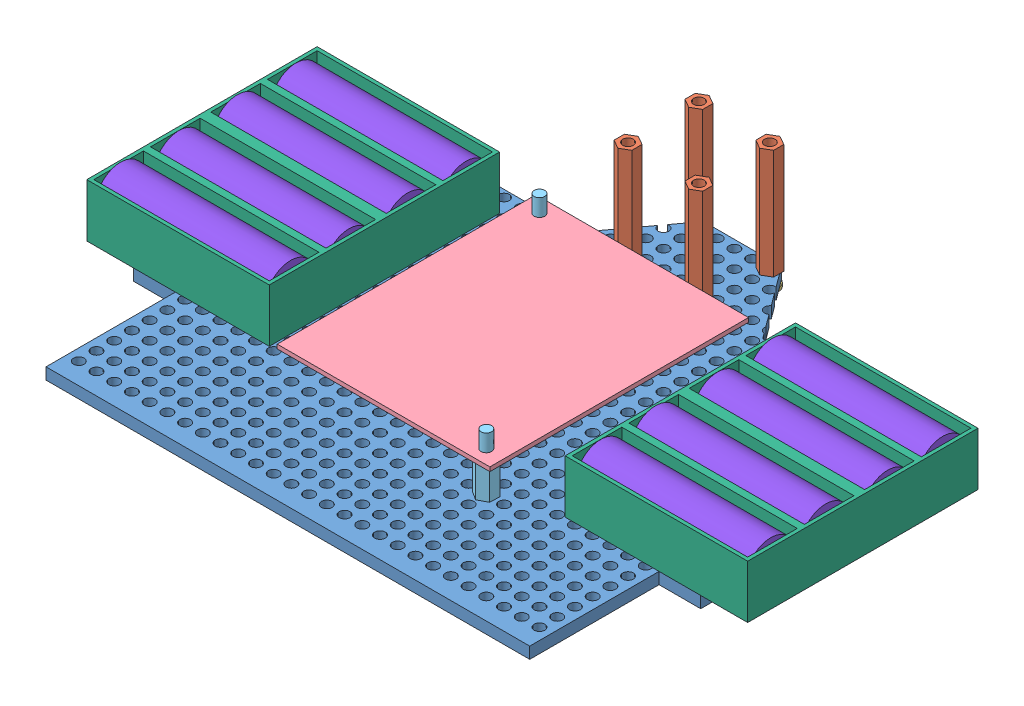
SolidWorks assembly 5-6-7, configuration Default. Lengths in mm.
Overall size (186.5 35.73 128.89).
32 component instances, 8 part files, 132 mates.
Components (placement in the parent):
- 6-0-1-1: 6-0-1 [Default] at origin size (160 3.25 128.29)
- 5-0-1-1: 5-0-1 [Default] at (10 3.25 -33.75) size (5 31 5.77)
- 5-0-1-2: 5-0-1 [Default] at (-10 3.25 -53.75) size (5 31 5.77)
- 5-0-1-3: 5-0-1 [Default] at (10 3.25 -53.75) size (5 31 5.77)
- 5-0-1-4: 5-0-1 [Default] at (-10 3.25 -33.75) size (5 31 5.77)
- 9-3-1-1: 9-3-1 [Default] at (10 9 -53.75) x (-1 0 0) z (0 0 1) size (5 10.48 5)
- 9-3-1-2: 9-3-1 [Default] at (-10 9 -33.75) x (1 0 0) z (0 0 -1) size (5 10.48 5)
- 9-3-1-3: 9-3-1 [Default] at (-10 9 -53.75) x (-1 0 0) z (0 0 1) size (5 10.48 5)
- 9-3-1-4: 9-3-1 [Default] at (10 9 -33.75) x (1 0 0) z (0 0 -1) size (5 10.48 5)
- 7-0-1-1: 7-0-1 [Default] at (0 13.25 8.75) size (60 1.17 73)
- 5-1-1-1: 5-1-1 [Default] at (-25 3.25 -23.75) size (5 16 5.77)
- 5-1-1-2: 5-1-1 [Default] at (25 3.25 41.25) x (0.999069 0 0.043139) z (-0.043139 0 0.999069) size (5 16 5.77)
- 9-3-1-5: 9-3-1 [Default] at (25 9 41.25) x (1 0 0) z (0 0 -1) size (5 10.48 5)
- 9-3-1-6: 9-3-1 [Default] at (-25 9 -23.75) x (1 0 0) z (0 0 -1) size (5 10.48 5)
- 6-1-1-5: 6-1-1 [Default] at (-67.5 3.25 3.25) size (51.5 15 65)
- 6-1-1-7: 6-1-1 [Default] at (67.5 3.25 3.25) size (51.5 15 65)
- 9-1-1-1: 9-1-1 [Default] at (-60 5 -18.75) x (-1 0 0) z (0 0 1) size (5 6.48 5)
- 9-1-1-2: 9-1-1 [Default] at (-60 5 16.25) x (-1 0 0) z (0 0 1) size (5 6.48 5)
- 9-1-1-3: 9-1-1 [Default] at (-75 5 -18.75) x (-1 0 0) z (0 0 1) size (5 6.48 5)
- 9-1-1-4: 9-1-1 [Default] at (-75 5 16.25) x (-1 0 0) z (0 0 1) size (5 6.48 5)
- 9-1-1-5: 9-1-1 [Default] at (60 5 -18.75) x (1 0 0) z (0 0 -1) size (5 6.48 5)
- 9-1-1-6: 9-1-1 [Default] at (60 5 16.25) x (-1 0 0) z (0 0 1) size (5 6.48 5)
- 9-1-1-7: 9-1-1 [Default] at (75 5 16.25) x (-1 0 0) z (0 0 1) size (5 6.48 5)
- 9-1-1-8: 9-1-1 [Default] at (75 5 -18.75) x (1 0 0) z (0 0 -1) size (5 6.48 5)
- 6-3-1-1: 6-3-1 [Default] at (-91.75 12.25 27.75) x (0 -1 0) z (0 0 1) size (14 49.5 14)
- 6-3-1-2: 6-3-1 [Default] at (-43.25 12.25 11.75) x (0 -1 0) z (0 0 -1) size (14 49.5 14)
- 6-3-1-3: 6-3-1 [Default] at (-91.75 12.25 -5.25) x (0 1 0) z (0 0 -1) size (14 49.5 14)
- 6-3-1-4: 6-3-1 [Default] at (-43.25 12.25 -21.25) x (0 -1 0) z (0 0 -1) size (14 49.5 14)
- 6-3-1-5: 6-3-1 [Default] at (91.75 12.25 27.75) x (0 1 0) z (0 0 1) size (14 49.5 14)
- 6-3-1-6: 6-3-1 [Default] at (43.25 12.25 11.75) x (0 -1 0) z (0 0 1) size (14 49.5 14)
- 6-3-1-7: 6-3-1 [Default] at (91.75 12.25 -5.25) x (0 1 0) z (0 0 1) size (14 49.5 14)
- 6-3-1-8: 6-3-1 [Default] at (43.25 12.25 -21.25) x (0 -1 0) z (0 0 1) size (14 49.5 14)
Mates (geometry in assembly coordinates):
- Coincident1: coincident anti-aligned: plane of 6-0-1-1 through (0 3.25 0) normal (0 1 0); plane of 5-0-1-3 through (10 3.25 -53.75) normal (0 -1 0)
- Parallel1: parallel aligned: plane of 6-0-1-1 through (0 0 0) normal (1 0 0); plane of 5-0-1-3 through (10 3.25 -53.75) normal (1 0 0)
- Concentric2: concentric aligned: cylinder of 6-0-1-1 through (10 3.25 -53.75) axis (0 -1 0) radius 1.5025; cylinder of 5-0-1-3 through (10 9.255 -53.75) axis (0 -1 0) radius 1.5025
- Coincident3: coincident anti-aligned: plane of 6-0-1-1 through (0 3.25 0) normal (0 1 0); plane of 5-0-1-2 through (-10 3.25 -53.75) normal (0 -1 0)
- Concentric3: concentric aligned: cylinder of 6-0-1-1 through (-10 3.25 -53.75) axis (0 -1 0) radius 1.5025; cylinder of 5-0-1-2 through (-10 9.255 -53.75) axis (0 -1 0) radius 1.5025
- Parallel2: parallel aligned: plane of 6-0-1-1 through (0 0 0) normal (1 0 0); plane of 5-0-1-2 through (-10 3.25 -53.75) normal (1 0 0)
- Coincident5: coincident anti-aligned: plane of 6-0-1-1 through (0 3.25 0) normal (0 1 0); plane of 5-0-1-4 through (-10 3.25 -33.75) normal (0 -1 0)
- Concentric4: concentric aligned: cylinder of 6-0-1-1 through (-10 3.25 -33.75) axis (0 -1 0) radius 1.5025; cylinder of 5-0-1-4 through (-10 9.255 -33.75) axis (0 -1 0) radius 1.5025
- Parallel3: parallel aligned: plane of 6-0-1-1 through (0 0 0) normal (1 0 0); plane of 5-0-1-4 through (-10 3.25 -33.75) normal (1 0 0)
- Coincident7: coincident anti-aligned: plane of 6-0-1-1 through (0 3.25 0) normal (0 1 0); plane of 5-0-1-1 through (10 3.25 -33.75) normal (0 -1 0)
- Concentric5: concentric aligned: cylinder of 6-0-1-1 through (10 3.25 -33.75) axis (0 -1 0) radius 1.5025; cylinder of 5-0-1-1 through (10 9.255 -33.75) axis (0 -1 0) radius 1.5025
- Parallel4: parallel aligned: plane of 6-0-1-1 through (0 0 0) normal (1 0 0); plane of 5-0-1-1 through (10 3.25 -33.75) normal (1 0 0)
- Concentric6: concentric anti-aligned: cylinder of 5-0-1-2 through (-10 9.255 -53.75) axis (0 -1 0) radius 1.5025; cylinder of 9-3-1-3 through (-10 0 -53.75) axis (0 1 0) radius 1.5
- Coincident9: coincident anti-aligned: plane of 6-0-1-1 through (0 0 0) normal (0 -1 0); plane of 9-3-1-3 through (-10 0 -53.75) normal (0 1 0)
- Parallel5: parallel anti-aligned: plane of 6-0-1-1 through (0 0 0) normal (1 0 0); plane of 9-3-1-3
- Concentric7: concentric anti-aligned: cylinder of 5-0-1-3 through (10 9.255 -53.75) axis (0 -1 0) radius 1.5025; cylinder of 9-3-1-1 through (10 0 -53.75) axis (0 1 0) radius 1.5
- Coincident11: coincident anti-aligned: plane of 6-0-1-1 through (0 0 0) normal (0 -1 0); plane of 9-3-1-1 through (10 0 -53.75) normal (0 1 0)
- Parallel6: parallel anti-aligned: plane of 6-0-1-1 through (0 0 0) normal (1 0 0); plane of 9-3-1-1
- Concentric8: concentric anti-aligned: cylinder of 5-0-1-4 through (-10 9.255 -33.75) axis (0 -1 0) radius 1.5025; cylinder of 9-3-1-2 through (-10 0 -33.75) axis (0 1 0) radius 1.5
- Coincident13: coincident anti-aligned: plane of 6-0-1-1 through (0 0 0) normal (0 -1 0); plane of 9-3-1-2 through (-10 0 -33.75) normal (0 1 0)
- Parallel7: parallel aligned: plane of 6-0-1-1 through (0 0 0) normal (1 0 0); plane of 9-3-1-2
- Concentric9: concentric anti-aligned: cylinder of 5-0-1-1 through (10 9.255 -33.75) axis (0 -1 0) radius 1.5025; cylinder of 9-3-1-4 through (10 0 -33.75) axis (0 1 0) radius 1.5
- Coincident15: coincident anti-aligned: plane of 6-0-1-1 through (0 0 0) normal (0 -1 0); plane of 9-3-1-4 through (10 0 -33.75) normal (0 1 0)
- Parallel8: parallel aligned: plane of 6-0-1-1 through (0 0 0) normal (1 0 0); plane of 9-3-1-4
- Coincident23: coincident anti-aligned: plane of 6-0-1-1 through (0 3.25 0) normal (0 1 0); plane of 5-1-1-1 through (-25 3.25 -23.75) normal (0 -1 0)
- Coincident24: coincident anti-aligned: plane of 6-0-1-1 through (0 3.25 0) normal (0 1 0); plane of 5-1-1-2 through (25 3.25 41.25) normal (0 -1 0)
- Concentric10: concentric aligned: cylinder of 6-0-1-1 through (-25 3.25 -23.75) axis (0 -1 0) radius 1.5025; cylinder of 5-1-1-1 through (-25 9.255 -23.75) axis (0 -1 0) radius 1.5025
- Parallel9: parallel aligned: plane of 6-0-1-1 through (0 0 0) normal (1 0 0); plane of 5-1-1-1 through (-25 3.25 -23.75) normal (1 0 0)
- Concentric11: concentric anti-aligned: cylinder of 7-0-1-1 through (-25 14.42 -23.75) axis (0 -1 0) radius 1.5025; cylinder of 5-1-1-1 through (-25 13.25 -23.75) axis (0 1 0) radius 1.5
- Coincident26: coincident anti-aligned: plane of 7-0-1-1 through (0 13.25 8.75) normal (0 -1 0); plane of 5-1-1-1 through (-25 13.25 -23.75) normal (0 1 0)
- Coincident27: coincident anti-aligned: plane of 7-0-1-1 through (0 13.25 8.75) normal (0 -1 0); plane of 5-1-1-2 through (25 13.25 41.25) normal (0 1 0)
- Concentric12: concentric aligned: cylinder of 6-0-1-1 through (25 3.25 41.25) axis (0 -1 0) radius 1.5025; cylinder of 5-1-1-2 through (25 9.255 41.25) axis (0 -1 0) radius 1.5025
- Concentric13: concentric anti-aligned: cylinder of 7-0-1-1 through (25 14.42 41.25) axis (0 -1 0) radius 1.5025; cylinder of 5-1-1-2 through (25 13.25 41.25) axis (0 1 0) radius 1.5
- Concentric14: concentric anti-aligned: cylinder of 5-1-1-1 through (-25 9.255 -23.75) axis (0 -1 0) radius 1.5025; cylinder of 9-3-1-6 through (-25 0 -23.75) axis (0 1 0) radius 1.5
- Coincident28: coincident anti-aligned: plane of 6-0-1-1 through (0 0 0) normal (0 -1 0); plane of 9-3-1-6 through (-25 0 -23.75) normal (0 1 0)
- Parallel10: parallel aligned: plane of 6-0-1-1 through (0 0 0) normal (1 0 0); plane of 9-3-1-6
- Concentric15: concentric anti-aligned: cylinder of 5-1-1-2 through (25 9.255 41.25) axis (0 -1 0) radius 1.5025; cylinder of 9-3-1-5 through (25 0 41.25) axis (0 1 0) radius 1.5
- Coincident30: coincident anti-aligned: plane of 6-0-1-1 through (0 0 0) normal (0 -1 0); plane of 9-3-1-5 through (25 0 41.25) normal (0 1 0)
- Parallel11: parallel aligned: plane of 6-0-1-1 through (0 0 0) normal (1 0 0); plane of 9-3-1-5
- Coincident31: coincident anti-aligned: plane of 6-0-1-1 through (0 3.25 0) normal (0 1 0); plane of 6-1-1-5 through (-67.5 3.25 3.25) normal (0 -1 0)
- Coincident32: coincident aligned: plane of 6-0-1-1 through (0 3.25 35.75) normal (0 0 1); plane of 6-1-1-5 through (-93.25 18.25 35.75) normal (0 0 1)
- Concentric16: concentric aligned: cylinder of 6-0-1-1 through (-75 3.25 -18.75) axis (0 -1 0) radius 1.5025; cylinder of 6-1-1-5 through (-75 18.25 -18.75) axis (0 -1 0) radius 1.5025
- Concentric17: concentric aligned: cylinder of 6-0-1-1 through (-75 3.25 16.25) axis (0 -1 0) radius 1.5025; cylinder of 6-1-1-5 through (-75 18.25 16.25) axis (0 -1 0) radius 1.5025
- Concentric20: concentric aligned: cylinder of 6-0-1-1 through (-60 3.25 -18.75) axis (0 -1 0) radius 1.5025; cylinder of 6-1-1-5 through (-60 18.25 -18.75) axis (0 -1 0) radius 1.5025
- Concentric21: concentric aligned: cylinder of 6-0-1-1 through (-60 3.25 16.25) axis (0 -1 0) radius 1.5025; cylinder of 6-1-1-5 through (-60 18.25 16.25) axis (0 -1 0) radius 1.5025
- Coincident37: coincident anti-aligned: plane of 6-0-1-1 through (0 3.25 0) normal (0 1 0); plane of 6-1-1-7 through (67.5 3.25 3.25) normal (0 -1 0)
- Coincident38: coincident aligned: plane of 6-0-1-1 through (0 3.25 35.75) normal (0 0 1); plane of 6-1-1-7 through (41.75 18.25 35.75) normal (0 0 1)
- Concentric22: concentric aligned: cylinder of 6-0-1-1 through (75 3.25 -18.75) axis (0 -1 0) radius 1.5025; cylinder of 6-1-1-7 through (75 18.25 -18.75) axis (0 -1 0) radius 1.5025
- Concentric23: concentric aligned: cylinder of 6-0-1-1 through (60 3.25 -18.75) axis (0 -1 0) radius 1.5025; cylinder of 6-1-1-7 through (60 18.25 -18.75) axis (0 -1 0) radius 1.5025
- Concentric24: concentric aligned: cylinder of 6-0-1-1 through (75 3.25 16.25) axis (0 -1 0) radius 1.5025; cylinder of 6-1-1-7 through (75 18.25 16.25) axis (0 -1 0) radius 1.5025
- Concentric25: concentric aligned: cylinder of 6-0-1-1 through (60 3.25 16.25) axis (0 -1 0) radius 1.5025; cylinder of 6-1-1-7 through (60 18.25 16.25) axis (0 -1 0) radius 1.5025
- Concentric26: concentric anti-aligned: cylinder of 6-1-1-7 through (75 18.25 -18.75) axis (0 -1 0) radius 1.5025; cylinder of 9-1-1-8 through (75 0 -18.75) axis (0 1 0) radius 1.5
- Coincident39: coincident anti-aligned: plane of 6-0-1-1 through (0 0 0) normal (0 -1 0); plane of 9-1-1-8 through (75 0 -18.75) normal (0 1 0)
- Parallel12: parallel aligned: plane of 6-0-1-1 through (0 0 0) normal (1 0 0); plane of 9-1-1-8
- Concentric27: concentric anti-aligned: cylinder of 6-1-1-7 through (60 18.25 -18.75) axis (0 -1 0) radius 1.5025; cylinder of 9-1-1-5 through (60 0 -18.75) axis (0 1 0) radius 1.5
- Coincident41: coincident anti-aligned: plane of 6-0-1-1 through (0 0 0) normal (0 -1 0); plane of 9-1-1-5 through (60 0 -18.75) normal (0 1 0)
- Parallel13: parallel aligned: plane of 6-0-1-1 through (0 0 0) normal (1 0 0); plane of 9-1-1-5
- Concentric28: concentric anti-aligned: cylinder of 6-1-1-7 through (75 18.25 16.25) axis (0 -1 0) radius 1.5025; cylinder of 9-1-1-7 through (75 0 16.25) axis (0 1 0) radius 1.5
- Coincident43: coincident anti-aligned: plane of 6-0-1-1 through (0 0 0) normal (0 -1 0); plane of 9-1-1-7 through (75 0 16.25) normal (0 1 0)
- Parallel14: parallel anti-aligned: plane of 6-0-1-1 through (0 0 0) normal (1 0 0); plane of 9-1-1-7
- Concentric29: concentric anti-aligned: cylinder of 6-1-1-7 through (60 18.25 16.25) axis (0 -1 0) radius 1.5025; cylinder of 9-1-1-6 through (60 0 16.25) axis (0 1 0) radius 1.5
- Coincident45: coincident anti-aligned: plane of 6-0-1-1 through (0 0 0) normal (0 -1 0); plane of 9-1-1-6 through (60 0 16.25) normal (0 1 0)
- Parallel15: parallel anti-aligned: plane of 6-0-1-1 through (0 0 0) normal (1 0 0); plane of 9-1-1-6
- Concentric30: concentric anti-aligned: cylinder of 6-1-1-5 through (-75 18.25 16.25) axis (0 -1 0) radius 1.5025; cylinder of 9-1-1-4 through (-75 0 16.25) axis (0 1 0) radius 1.5
- Coincident47: coincident anti-aligned: plane of 6-0-1-1 through (0 0 0) normal (0 -1 0); plane of 9-1-1-4 through (-75 0 16.25) normal (0 1 0)
- Parallel16: parallel anti-aligned: plane of 6-0-1-1 through (0 0 0) normal (1 0 0); plane of 9-1-1-4
- Concentric31: concentric anti-aligned: cylinder of 6-1-1-5 through (-60 18.25 16.25) axis (0 -1 0) radius 1.5025; cylinder of 9-1-1-2 through (-60 0 16.25) axis (0 1 0) radius 1.5
- Coincident49: coincident anti-aligned: plane of 6-0-1-1 through (0 0 0) normal (0 -1 0); plane of 9-1-1-2 through (-60 0 16.25) normal (0 1 0)
- Parallel17: parallel anti-aligned: plane of 6-0-1-1 through (0 0 0) normal (1 0 0); plane of 9-1-1-2
- Concentric32: concentric anti-aligned: cylinder of 6-1-1-5 through (-75 18.25 -18.75) axis (0 -1 0) radius 1.5025; cylinder of 9-1-1-3 through (-75 0 -18.75) axis (0 1 0) radius 1.5
- Coincident51: coincident anti-aligned: plane of 6-0-1-1 through (0 0 0) normal (0 -1 0); plane of 9-1-1-3 through (-75 0 -18.75) normal (0 1 0)
- Parallel18: parallel anti-aligned: plane of 6-0-1-1 through (0 0 0) normal (1 0 0); plane of 9-1-1-3
- Concentric33: concentric anti-aligned: cylinder of 6-1-1-5 through (-60 18.25 -18.75) axis (0 -1 0) radius 1.5025; cylinder of 9-1-1-1 through (-60 0 -18.75) axis (0 1 0) radius 1.5
- Coincident53: coincident anti-aligned: plane of 6-0-1-1 through (0 0 0) normal (0 -1 0); plane of 9-1-1-1 through (-60 0 -18.75) normal (0 1 0)
- Parallel19: parallel anti-aligned: plane of 6-0-1-1 through (0 0 0) normal (1 0 0); plane of 9-1-1-1
- Parallel20: parallel aligned: plane of 6-1-1-5 through (-67.5 3.25 3.25) normal (0 0 1); plane of 6-3-1-1 through (-91.75 12.25 27.75) normal (0 0 1)
- Parallel21: parallel anti-aligned: plane of 6-1-1-5 through (-67.5 3.25 3.25) normal (0 0 1); plane of 6-3-1-2 through (-43.25 12.25 11.75) normal (0 0 -1)
- Coincident60: coincident anti-aligned: plane of 6-1-1-5 through (-92.25 5.25 4.75) normal (1 0 0); plane of 6-3-1-1 through (-92.25 12.25 27.75) normal (-1 0 0)
- Coincident61: coincident anti-aligned: plane of 6-1-1-5 through (-92.25 5.25 4.75) normal (1 0 0); plane of 6-3-1-1 through (-92.25 12.25 27.75) normal (-1 0 0)
- Coincident62: coincident anti-aligned: plane of 6-1-1-5 through (-42.75 5.25 4.75) normal (-1 0 0); plane of 6-3-1-1 through (-42.75 12.25 27.75) normal (1 0 0)
- Tangent6: tangent anti-aligned: plane of 6-1-1-5 through (-67.5 5.25 3.25) normal (0 1 0); cylinder of 6-3-1-1 through (-43.75 12.25 27.75) axis (-1 0 0) radius 7
- Tangent8: tangent anti-aligned: plane of 6-1-1-5 through (-92.25 5.25 34.75) normal (0 0 -1); cylinder of 6-3-1-1 through (-43.75 12.25 27.75) axis (-1 0 0) radius 7
- Coincident63: coincident anti-aligned: plane of 6-1-1-5 through (-42.75 5.25 4.75) normal (-1 0 0); plane of 6-3-1-2 through (-42.75 12.25 11.75) normal (1 0 0)
- Coincident64: coincident anti-aligned: plane of 6-1-1-5 through (-42.75 5.25 4.75) normal (-1 0 0); plane of 6-3-1-2 through (-42.75 12.25 11.75) normal (1 0 0)
- Coincident65: coincident anti-aligned: plane of 6-1-1-5 through (-92.25 5.25 4.75) normal (1 0 0); plane of 6-3-1-2 through (-92.25 12.25 11.75) normal (-1 0 0)
- Tangent9: tangent anti-aligned: plane of 6-1-1-5 through (-67.5 5.25 3.25) normal (0 1 0); cylinder of 6-3-1-2 through (-91.25 12.25 11.75) axis (1 0 0) radius 7
- Tangent10: tangent anti-aligned: plane of 6-1-1-5 through (-92.25 5.25 4.75) normal (0 0 1); cylinder of 6-3-1-2 through (-91.25 12.25 11.75) axis (1 0 0) radius 7
- Parallel22: parallel anti-aligned: plane of 6-1-1-5 through (-67.5 3.25 3.25) normal (0 0 1); plane of 6-3-1-3 through (-91.75 12.25 -5.25) normal (0 0 -1)
- Parallel23: parallel anti-aligned: plane of 6-1-1-5 through (-67.5 3.25 3.25) normal (0 0 1); plane of 6-3-1-4 through (-43.25 12.25 -21.25) normal (0 0 -1)
- Coincident74: coincident anti-aligned: plane of 6-1-1-7 through (92.25 5.25 4.75) normal (-1 0 0); plane of 6-3-1-5 through (92.25 12.25 27.75) normal (1 0 0)
- Coincident75: coincident anti-aligned: plane of 6-1-1-7 through (92.25 5.25 4.75) normal (-1 0 0); plane of 6-3-1-5 through (92.25 12.25 27.75) normal (1 0 0)
- Coincident76: coincident anti-aligned: plane of 6-1-1-7 through (42.75 5.25 4.75) normal (1 0 0); plane of 6-3-1-5 through (42.75 12.25 27.75) normal (-1 0 0)
- Tangent15: tangent anti-aligned: plane of 6-1-1-7 through (67.5 5.25 3.25) normal (0 1 0); cylinder of 6-3-1-5 through (43.75 12.25 27.75) axis (1 0 0) radius 7
- Tangent16: tangent anti-aligned: plane of 6-1-1-7 through (42.75 5.25 34.75) normal (0 0 -1); cylinder of 6-3-1-5 through (43.75 12.25 27.75) axis (1 0 0) radius 7
- Parallel24: parallel aligned: plane of 6-1-1-7 through (67.5 3.25 3.25) normal (0 0 1); plane of 6-3-1-5 through (91.75 12.25 27.75) normal (0 0 1)
- Coincident90: coincident anti-aligned: plane of 6-1-1-7 through (42.75 5.25 4.75) normal (1 0 0); plane of 6-3-1-6 through (42.75 12.25 11.75) normal (-1 0 0)
- Coincident91: coincident anti-aligned: plane of 6-1-1-7 through (42.75 5.25 4.75) normal (1 0 0); plane of 6-3-1-6 through (42.75 12.25 11.75) normal (-1 0 0)
- Coincident92: coincident anti-aligned: plane of 6-1-1-7 through (92.25 5.25 4.75) normal (-1 0 0); plane of 6-3-1-6 through (92.25 12.25 11.75) normal (1 0 0)
- Tangent24: tangent anti-aligned: plane of 6-1-1-7 through (67.5 5.25 3.25) normal (0 1 0); cylinder of 6-3-1-6 through (91.25 12.25 11.75) axis (-1 0 0) radius 7
- Tangent25: tangent anti-aligned: plane of 6-1-1-7 through (42.75 5.25 4.75) normal (0 0 1); cylinder of 6-3-1-6 through (91.25 12.25 11.75) axis (-1 0 0) radius 7
- Parallel28: parallel aligned: plane of 6-1-1-7 through (67.5 3.25 3.25) normal (0 0 1); plane of 6-3-1-6 through (43.25 12.25 11.75) normal (0 0 1)
- Parallel29: parallel aligned: plane of 6-1-1-7 through (67.5 3.25 3.25) normal (0 0 1); plane of 6-3-1-7 through (91.75 12.25 -5.25) normal (0 0 1)
- Parallel30: parallel aligned: plane of 6-3-1-8 through (43.25 12.25 -21.25) normal (0 0 1); plane of assembly through (0 0 0) normal (0 0 1)
- Coincident103: coincident anti-aligned: plane of 6-1-1-5 through (-92.25 5.25 1.75) normal (1 0 0); plane of 6-3-1-3 through (-92.25 12.25 -5.25) normal (-1 0 0)
- Coincident104: coincident anti-aligned: plane of 6-1-1-5 through (-92.25 5.25 1.75) normal (1 0 0); plane of 6-3-1-3 through (-92.25 12.25 -5.25) normal (-1 0 0)
- Coincident105: coincident anti-aligned: plane of 6-1-1-5 through (-42.75 5.25 1.75) normal (-1 0 0); plane of 6-3-1-3 through (-42.75 12.25 -5.25) normal (1 0 0)
- Tangent35: tangent anti-aligned: plane of 6-1-1-5 through (-67.5 5.25 3.25) normal (0 1 0); cylinder of 6-3-1-3 through (-43.75 12.25 -5.25) axis (-1 0 0) radius 7
- Tangent36: tangent anti-aligned: plane of 6-1-1-5 through (-92.25 5.25 1.75) normal (0 0 -1); cylinder of 6-3-1-3 through (-43.75 12.25 -5.25) axis (-1 0 0) radius 7
- Coincident106: coincident anti-aligned: plane of 6-1-1-5 through (-42.75 5.25 -14.25) normal (-1 0 0); plane of 6-3-1-4 through (-42.75 12.25 -21.25) normal (1 0 0)
- Coincident107: coincident anti-aligned: plane of 6-1-1-5 through (-42.75 5.25 -14.25) normal (-1 0 0); plane of 6-3-1-4 through (-42.75 12.25 -21.25) normal (1 0 0)
- Coincident109: coincident anti-aligned: plane of 6-1-1-5 through (-92.25 5.25 -14.25) normal (1 0 0); plane of 6-3-1-4 through (-92.25 12.25 -21.25) normal (-1 0 0)
- Tangent38: tangent anti-aligned: plane of 6-1-1-5 through (-67.5 5.25 3.25) normal (0 1 0); cylinder of 6-3-1-4 through (-91.25 12.25 -21.25) axis (1 0 0) radius 7
- Tangent39: tangent anti-aligned: plane of 6-1-1-5 through (-92.25 5.25 -14.25) normal (0 0 -1); cylinder of 6-3-1-4 through (-91.25 12.25 -21.25) axis (1 0 0) radius 7
- Tangent40: tangent anti-aligned: plane of 6-1-1-5 through (-92.25 5.25 -28.25) normal (0 0 1); cylinder of 6-3-1-4 through (-91.25 12.25 -21.25) axis (1 0 0) radius 7
- Tangent41: tangent anti-aligned: plane of 6-1-1-5 through (-92.25 5.25 -12.25) normal (0 0 1); cylinder of 6-3-1-3 through (-43.75 12.25 -5.25) axis (-1 0 0) radius 7
- Tangent42: tangent anti-aligned: plane of 6-1-1-5 through (-92.25 5.25 4.75) normal (0 0 1); cylinder of 6-3-1-2 through (-91.25 12.25 11.75) axis (1 0 0) radius 7
- Coincident110: coincident anti-aligned: plane of 6-1-1-7 through (92.25 5.25 1.75) normal (-1 0 0); plane of 6-3-1-7 through (92.25 12.25 -5.25) normal (1 0 0)
- Coincident111: coincident anti-aligned: plane of 6-1-1-7 through (92.25 5.25 1.75) normal (-1 0 0); plane of 6-3-1-7 through (92.25 12.25 -5.25) normal (1 0 0)
- Coincident112: coincident anti-aligned: plane of 6-1-1-7 through (42.75 5.25 1.75) normal (1 0 0); plane of 6-3-1-7 through (42.75 12.25 -5.25) normal (-1 0 0)
- Tangent43: tangent anti-aligned: plane of 6-1-1-7 through (67.5 5.25 3.25) normal (0 1 0); cylinder of 6-3-1-7 through (43.75 12.25 -5.25) axis (1 0 0) radius 7
- Tangent44: tangent anti-aligned: plane of 6-1-1-7 through (42.75 5.25 -12.25) normal (0 0 1); cylinder of 6-3-1-7 through (43.75 12.25 -5.25) axis (1 0 0) radius 7
- Tangent45: tangent anti-aligned: plane of 6-1-1-7 through (42.75 5.25 1.75) normal (0 0 -1); cylinder of 6-3-1-7 through (43.75 12.25 -5.25) axis (1 0 0) radius 7
- Coincident113: coincident anti-aligned: plane of 6-1-1-7 through (42.75 5.25 -14.25) normal (1 0 0); plane of 6-3-1-8 through (42.75 12.25 -21.25) normal (-1 0 0)
- Coincident114: coincident anti-aligned: plane of 6-1-1-7 through (42.75 5.25 -14.25) normal (1 0 0); plane of 6-3-1-8 through (42.75 12.25 -21.25) normal (-1 0 0)
- Coincident115: coincident anti-aligned: plane of 6-1-1-7 through (92.25 5.25 -14.25) normal (-1 0 0); plane of 6-3-1-8 through (92.25 12.25 -21.25) normal (1 0 0)
- Tangent46: tangent anti-aligned: plane of 6-1-1-7 through (67.5 5.25 3.25) normal (0 1 0); cylinder of 6-3-1-8 through (91.25 12.25 -21.25) axis (-1 0 0) radius 7
- Tangent47: tangent anti-aligned: plane of 6-1-1-7 through (42.75 5.25 -14.25) normal (0 0 -1); cylinder of 6-3-1-8 through (91.25 12.25 -21.25) axis (-1 0 0) radius 7
- Tangent48: tangent anti-aligned: plane of 6-1-1-7 through (42.75 5.25 -28.25) normal (0 0 1); cylinder of 6-3-1-8 through (91.25 12.25 -21.25) axis (-1 0 0) radius 7
- Tangent49: tangent anti-aligned: plane of 6-1-1-7 through (42.75 5.25 20.75) normal (0 0 1); cylinder of 6-3-1-5 through (43.75 12.25 27.75) axis (1 0 0) radius 7
- Tangent50: tangent anti-aligned: plane of 6-1-1-7 through (42.75 5.25 4.75) normal (0 0 1); cylinder of 6-3-1-6 through (91.25 12.25 11.75) axis (-1 0 0) radius 7
- Tangent51: tangent anti-aligned: plane of 6-1-1-7 through (42.75 5.25 -12.25) normal (0 0 1); cylinder of 6-3-1-7 through (43.75 12.25 -5.25) axis (1 0 0) radius 7
- Tangent52: tangent anti-aligned: plane of 6-1-1-7 through (42.75 5.25 -28.25) normal (0 0 1); cylinder of 6-3-1-8 through (91.25 12.25 -21.25) axis (-1 0 0) radius 7
